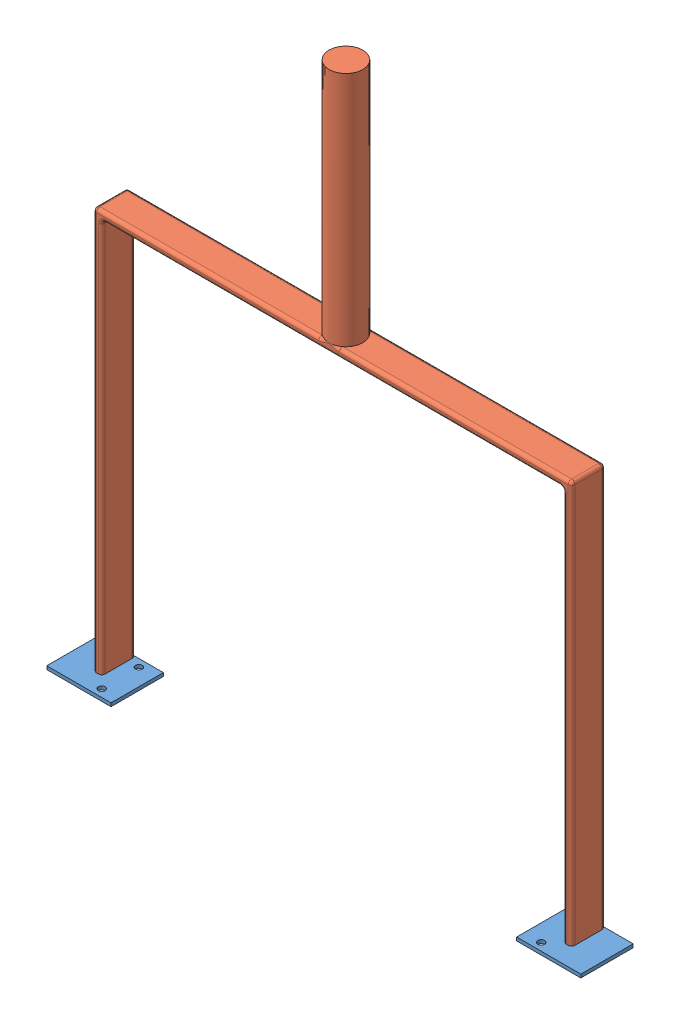
SolidWorks assembly Tachometer handle, configuration Default. Lengths in mm.
Overall size (158 190 15.5).
3 component instances, 2 part files, 3 mates.
Components (placement in the parent):
- Component mount-1: Component mount [Default] at (6.1514 8.8267 15.8201) size (19 1 15.5)
- Component mount-2: Component mount [Default] at (-137.4513 8.8267 16.3002) x (-1 0 0) z (0 0 -1) size (19 1 15.5)
- Part2^Tachometer handle-1: Part2^Tachometer handle [Default] at origin size (141.5 190 10) (virtual)
Mates (geometry in assembly coordinates):
- Coincident4: coincident aligned: plane of Component mount-1 through (6.1514 9.8267 15.8201) normal (0 1 0); plane of Component mount-2 through (-137.4513 9.8267 16.3002) normal (0 1 0)
- Distance1: distance = 120 mm anti-aligned: plane of Component mount-2 through (-125.6499 9.8267 8.3102) normal (1 0 0); plane of Component mount-1 through (-5.6499 9.8267 23.8102) normal (-1 0 0)
- Coincident3: coincident aligned: plane of Component mount-1 through (-5.6499 9.8267 23.8102) normal (0 0 1); plane of Component mount-2 through (-125.6499 9.8267 23.8102) normal (0 0 1)
